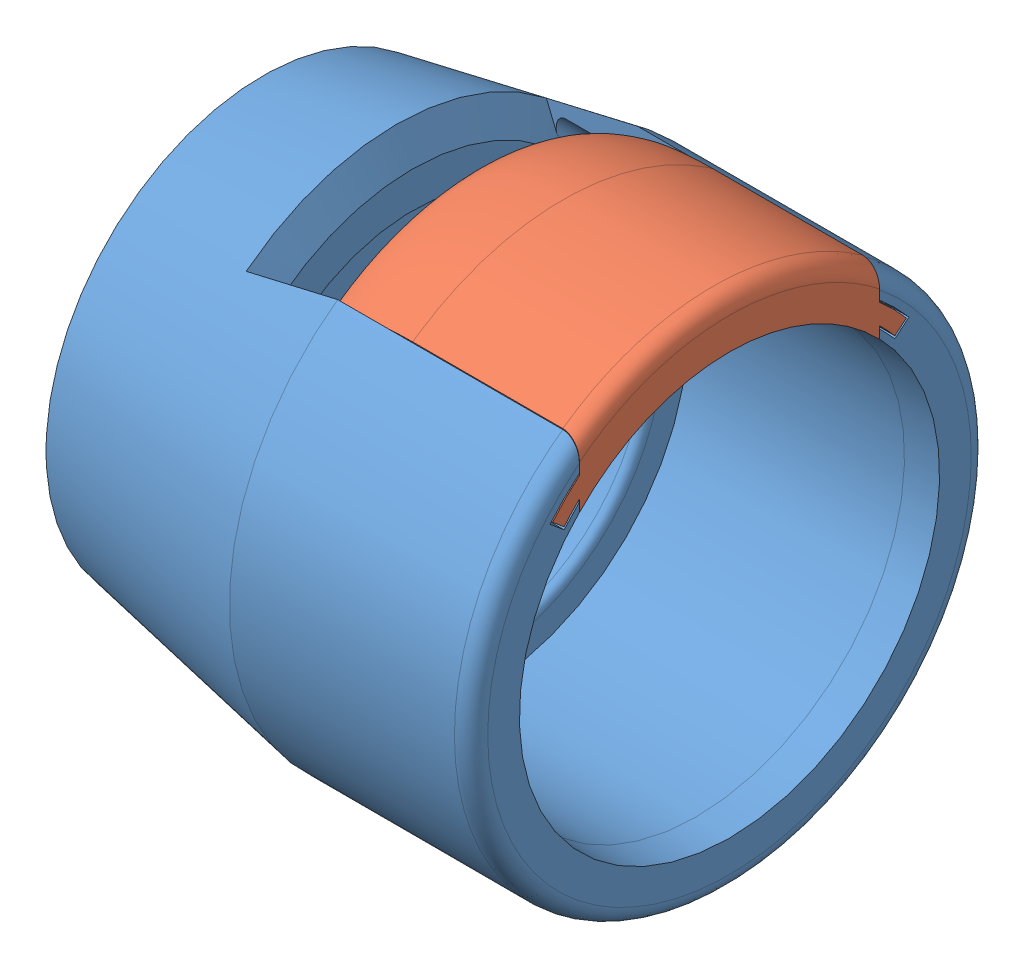
SolidWorks assembly Sestava1, configuration Výchozí. Lengths in mm.
Overall size (28.11 31.06 31).
2 component instances, 2 part files, 2 mates.
Components (placement in the parent):
- protiprakový kryt motoru-1: protiprakový kryt motoru [Výchozí] at (-6.547 -1.664 31) size (28.11 29.98 31)
- protiprakový kryt motoru (zásterka-1: protiprakový kryt motoru (zásterka [Výchozí] at (-21.547 -1.6101 31) size (15.09 7.03 21.22)
Mates (geometry in assembly coordinates):
- Sjednocená1: coincident aligned: plane of protiprakový kryt motoru-1 through (3.4467 -1.664 31) normal (1 0 0); plane of protiprakový kryt motoru (zásterka-1 through (3.4467 -1.6101 31) normal (1 0 0)
- Sjednocená2: coincident anti-aligned: plane of protiprakový kryt motoru-1 through (-15.5533 15.336 40) normal (0 0 -1); plane of protiprakový kryt motoru (zásterka-1 through (3.4467 -1.6101 40) normal (0 0 1)
